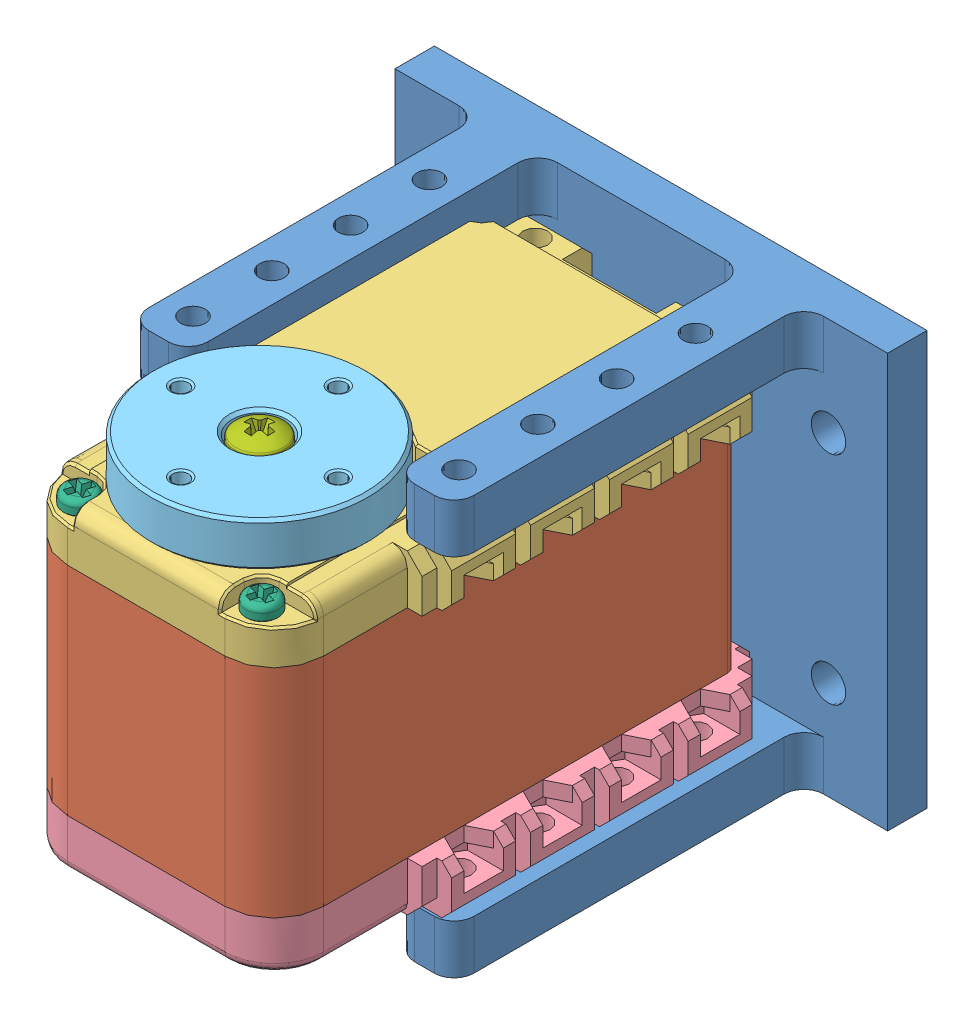
SolidWorks assembly ass_support_couderV3, configuration Défaut. Lengths in mm.
Overall size (50 42.55 54.25).
11 component instances, 7 part files, 3 mates.
Components (placement in the parent):
- support_couderV3-1: support_couderV3 [Défaut] at (-10.7404 1.2972 30.25) size (50 42 39.5)
- AX-12A-1: AX-12A [Default] at (-10.7404 1.2972 73) x (0 0 -1) z (0 1 0) size (50 32 40.55)
  - AX-12A-01-1: AX-12A-01 [Default] at origin size (48.5 26 22)
  - AX-12A-02-1: AX-12A-02 [Default] at (0 0 13.5) size (50 32 8)
  - AX-12A-03-1: AX-12A-03 [Default] at (0 0 -13.5) x (1 0 0) z (0 0 -1) size (50 32 8)
  - AX-12A-04-1: AX-12A-04 [Default] at (0 0 21) size (22 22 6.7)
  - SetScrew-5: SetScrew [Default] at (33 10.4 14.5) x (0.31498 0.949098 0) z (0 0 -1) size (3.3 3.3 29.44)
  - SetScrew-6: SetScrew [Default] at (-9 9.25 14.5) x (0.31498 0.949098 0) z (0 0 -1) size (3.3 3.3 29.44)
  - SetScrew-7: SetScrew [Default] at (-9 -9.25 14.5) x (-0.958559 0.284893 0) z (0 0 -1) size (3.3 3.3 29.44)
  - SetScrew-8: SetScrew [Default] at (33 -10.4 14.5) x (0.31498 0.949098 0) z (0 0 -1) size (3.3 3.3 29.44)
  - pan head cross recess screw_iso-1: pan head cross recess screw_iso [ISO 7045 - M2.5 x 8 - Z --- 8C] at (0 0 21.6) x (0 0 -1) z (1 0 0) size (10.05 5 5)
Mates (geometry in assembly coordinates):
- Coaxiale1: concentric aligned: cylinder of support_couderV3-1 through (-24.2404 -19.7028 42.25) axis (0 1 0) radius 1.25; cylinder of AX-12A-1/AX-12A-02-1 through (-24.2404 12.2962 42.25) axis (0 1 0) radius 1.25
- Coaxiale2: concentric aligned: cylinder of support_couderV3-1 through (-24.2404 -19.7028 66.25) axis (0 1 0) radius 1.25; cylinder of AX-12A-1/AX-12A-02-1 through (-24.2404 12.2962 66.25) axis (0 1 0) radius 1.25
- Coïncidente1: coincident anti-aligned: plane of support_couderV3-1 through (-27.2404 17.2972 69.75) normal (0 -1 0); plane of AX-12A-1/AX-12A-02-1 through (-10.7404 17.2972 73) normal (0 1 0)
